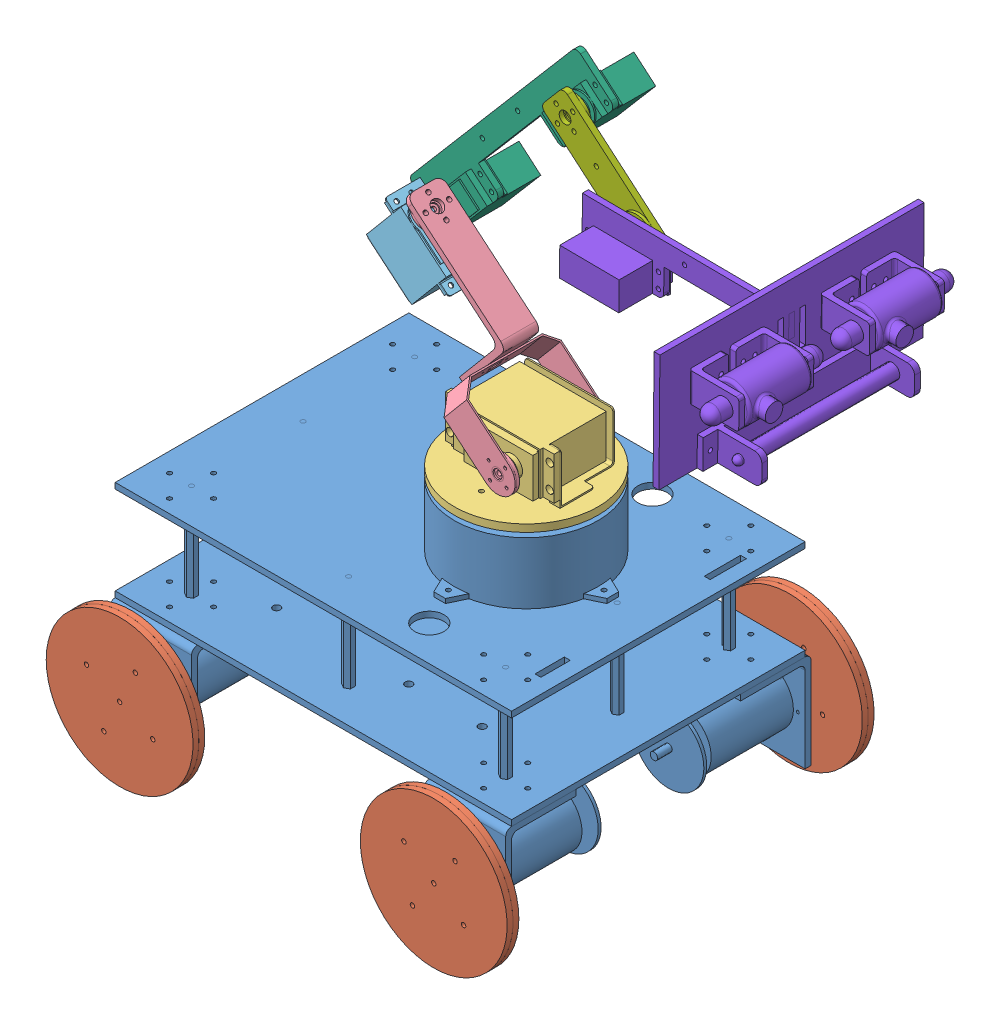
SolidWorks assembly exa_robot_part3, configuration Default. Lengths in mm.
Overall size (452.74 461.66 342.18).
11 component instances, 8 part files, 26 mates.
Components (placement in the parent):
- base_robot-1: base_robot [Default] at (14.2374 -23.114 -6.4589) size (270 179.13 234)
- roda_robot_fix-1: roda_robot_fix [Default] at (268.1239 -5.9891 251.6556) x (0.408711 0.912664 0) z (0 0 1) size (100 100 21)
- roda_robot_fix-2: roda_robot_fix [Default] at (-22.1829 120.8673 251.6556) x (-0.2415 -0.970401 0) z (0 0 1) size (100 100 21)
- roda_robot_fix-3: roda_robot_fix [Default] at (-43.3679 96.894 162.7099) x (0.933321 0.359042 0) z (0 0 -1) size (100 100 21)
- roda_robot_fix-4: roda_robot_fix [Default] at (229.5868 134.8934 162.7099) x (0.816348 -0.57756 0) z (0 0 -1) size (100 100 21)
- link1_robot-1: link1_robot [Default] at (14.2374 -23.114 -6.4589) size (98 43 98)
- link2_robot-1: link2_robot [Default] at (14.2374 -23.114 -6.4589) size (99.47 123.93 66)
- link3_robot-1: link3_robot [Default] at (14.2374 -23.114 -6.4589) size (56.44 54.96 29)
- link4_robot-1: link4_robot [Default] at (11.4345 -22.4006 -6.4589) x (0.999966 -0.008267 0) z (0 0 1) size (137.73 155 42.35)
- link5_robot-1: link5_robot [Default] at (11.4345 -22.4006 -6.4589) x (0.999966 -0.008267 0) z (0 0 1) size (81.1 72.97 14)
- link6_eof_robot-1: link6_eof_robot [Default] at (11.4345 -22.4006 -6.4589) x (0.999966 -0.008267 0) z (0 0 1) size (184.63 80 180)
Mates (geometry in assembly coordinates):
- Coincident1: coincident anti-aligned: plane of base_robot-1 through (258.5015 16.6149 311.1827) normal (0 0 1); plane of roda_robot_fix-1 through (235.6028 60.827 311.1827) normal (0 0 -1)
- Concentric1: concentric aligned: cylinder of base_robot-1 through (235.6028 60.827 324.1827) axis (0 0 -1) radius 2.5; cylinder of roda_robot_fix-1 through (235.6028 60.827 324.1827) axis (0 0 -1) radius 2.5
- Concentric2: concentric aligned: cylinder of base_robot-1 through (235.6028 60.827 90.1827) axis (0 0 1) radius 2.5; cylinder of roda_robot_fix-4 through (235.6028 60.827 90.1827) axis (0 0 1) radius 2.5
- Coincident3: coincident anti-aligned: plane of base_robot-1 through (212.704 16.6149 103.1827) normal (0 0 -1); plane of roda_robot_fix-4 through (235.6028 60.827 103.1827) normal (0 0 1)
- Coincident4: coincident anti-aligned: plane of base_robot-1 through (-1.296 105.0391 311.1827) normal (0 0 1); plane of roda_robot_fix-2 through (21.6028 60.827 311.1827) normal (0 0 -1)
- Concentric3: concentric aligned: cylinder of base_robot-1 through (21.6028 60.827 324.1827) axis (0 0 -1) radius 2.5; cylinder of roda_robot_fix-2 through (21.6028 60.827 324.1827) axis (0 0 -1) radius 2.5
- Coincident5: coincident anti-aligned: plane of base_robot-1 through (-1.296 16.6149 103.1827) normal (0 0 -1); plane of roda_robot_fix-3 through (21.6028 60.827 103.1827) normal (0 0 1)
- Concentric4: concentric aligned: cylinder of base_robot-1 through (21.6028 60.827 90.1827) axis (0 0 1) radius 2.5; cylinder of roda_robot_fix-3 through (21.6028 60.827 90.1827) axis (0 0 1) radius 2.5
- Coincident6: coincident anti-aligned: plane of base_robot-1 through (183.8898 208.9523 217.0887) normal (0 1 0); plane of link1_robot-1 through (173.6028 208.9523 207.1827) normal (0 -1 0)
- Concentric5: concentric aligned: cylinder of base_robot-1 through (173.6028 189.6967 207.1827) axis (0 1 0) radius 2.8131; cylinder of link1_robot-1 through (173.6028 204.9523 207.1827) axis (0 1 0) radius 3
- Coincident7: coincident anti-aligned: plane of link1_robot-1 through (189.1028 233.9523 239.1727) normal (0 0 1); plane of link2_robot-1 through (189.1028 233.9523 239.1727) normal (0 0 -1)
- Concentric6: concentric anti-aligned: cylinder of link1_robot-1 through (189.1028 233.9523 239.1727) axis (0 0 -1) radius 3; cylinder of link2_robot-1 through (189.1028 233.9523 236.1727) axis (0 0 1) radius 3
- Concentric7: concentric anti-aligned: cylinder of link2_robot-1 through (108.8974 331.277 208.7585) axis (0.642788 0.766044 0) radius 3; cylinder of link3_robot-1 through (110.8257 333.5751 208.7585) axis (-0.642788 -0.766044 0) radius 2.9972
- Coincident9: coincident anti-aligned: plane of link2_robot-1 through (110.8257 333.5751 208.7585) normal (-0.642788 -0.766044 0); plane of link3_robot-1 through (110.8257 333.5751 208.7585) normal (0.642788 0.766044 0)
- Coincident10: coincident anti-aligned: plane of link3_robot-1 through (99.1297 316.2635 192.7915) normal (0 0 -1); plane of link4_robot-1 through (99.1297 316.2635 192.7915) normal (0 0 1)
- Concentric8: concentric anti-aligned: cylinder of link3_robot-1 through (99.1297 316.2635 189.7915) axis (0 0 1) radius 3; cylinder of link4_robot-1 through (99.1297 316.2635 192.7915) axis (0 0 -1) radius 2.9972
- Coincident11: coincident anti-aligned: plane of link4_robot-1 through (191.6635 423.9248 192.7915) normal (0 0 1); plane of link5_robot-1 through (191.6635 423.9248 192.7915) normal (0 0 -1)
- Concentric9: concentric anti-aligned: cylinder of link4_robot-1 through (191.6635 423.9248 192.7915) axis (0 0 -1) radius 2.9972; cylinder of link5_robot-1 through (191.6635 423.9248 189.7915) axis (0 0 1) radius 3
- Coincident12: coincident anti-aligned: plane of link5_robot-1 through (241.87 381.0843 200.7915) normal (0 0 1); plane of link6_eof_robot-1 through (241.87 381.0843 200.7915) normal (0 0 -1)
- Concentric10: concentric anti-aligned: cylinder of link5_robot-1 through (241.87 381.0843 203.7915) axis (0 0 -1) radius 3; cylinder of link6_eof_robot-1 through (241.87 381.0843 200.7915) axis (0 0 1) radius 2.9972
- LimitAngle1: limit planar angle = 2.443461 rad anti-aligned: plane of link1_robot-1 through (173.6028 213.9523 207.1827) normal (0 1 0); plane of link2_robot-1 through (166.9546 268.2017 195.8793) normal (0.642788 0.766044 0)
- LimitAngle2: limit planar angle = 1.570796 rad anti-aligned: plane of link3_robot-1 through (93.6106 327.8772 218.7915) normal (-0.766044 0.642788 0); plane of link2_robot-1 through (109.4871 290.3828 220.7585) normal (0 0 1)
- LimitAngle3: limit planar angle = 1.562529 rad aligned: plane of link4_robot-1 through (100.5792 302.5054 177.361) normal (-0.649099 -0.760704 0); plane of link3_robot-1 through (93.6106 327.8772 218.7915) normal (-0.766044 0.642788 0)
- LimitAngle4: limit planar angle = 0 rad aligned: plane of link4_robot-1 through (190.214 437.683 177.361) normal (0.649099 0.760704 0); plane of link5_robot-1 through (190.3243 440.8425 198.7915) normal (0.649099 0.760704 0)
- LimitAngle5: limit planar angle = 2.268928 rad anti-aligned: plane of link5_robot-1 through (174.7459 422.5856 198.7915) normal (-0.649099 -0.760704 0); plane of link6_eof_robot-1 through (224.6686 374.3358 216.222) normal (-0.999966 0.008267 0)
- LimitAngle9: limit planar angle = 1.570796 rad anti-aligned: plane of link1_robot-1 through (203.1028 247.9523 225.1827) normal (1 0 0); plane of base_robot-1 through (200.3661 159.827 307.1827) normal (0 0 1)
